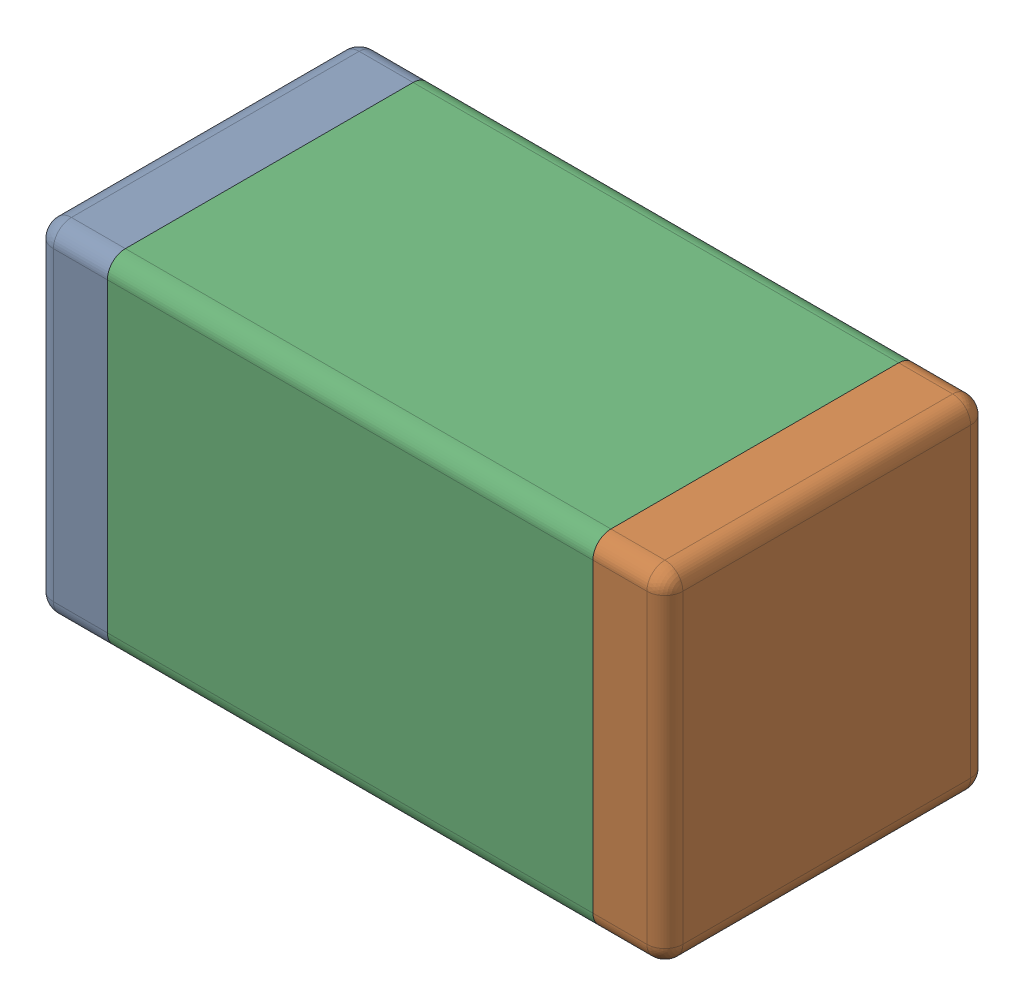
SolidWorks assembly C2, configuration Default. Lengths in mm.
Overall size (1.75 0.95 0.9).
6 component instances, 3 part files, 0 mates.
Components (placement in the parent):
- 6033537424-1: 6033537424 [Default] at (32.091 4.064 0) x (1 0 0) z (0 0 1) size (1.75 0.95 0.9)
  - Terminal_5-1: Terminal_5 [Default] at (-0.875 -0.475 0) size (1.75 0.95 0.9)
    - Open CASCADE STEP translator 6.8 142.1.1-1: Open CASCADE STEP translator 6.8 142.1.1 [Default] at origin size (0.2 0.95 0.9)
    - Open CASCADE STEP translator 6.8 142.1.2-1: Open CASCADE STEP translator 6.8 142.1.2 [Default] at origin size (0.2 0.95 0.9)
  - Mid_Body_2-1: Mid_Body_2 [Default] at (-0.875 -0.475 0) size (1.35 0.95 0.9)
    - Open CASCADE STEP translator 6.8 142.2.1-1: Open CASCADE STEP translator 6.8 142.2.1 [Default] at origin size (1.35 0.95 0.9)
